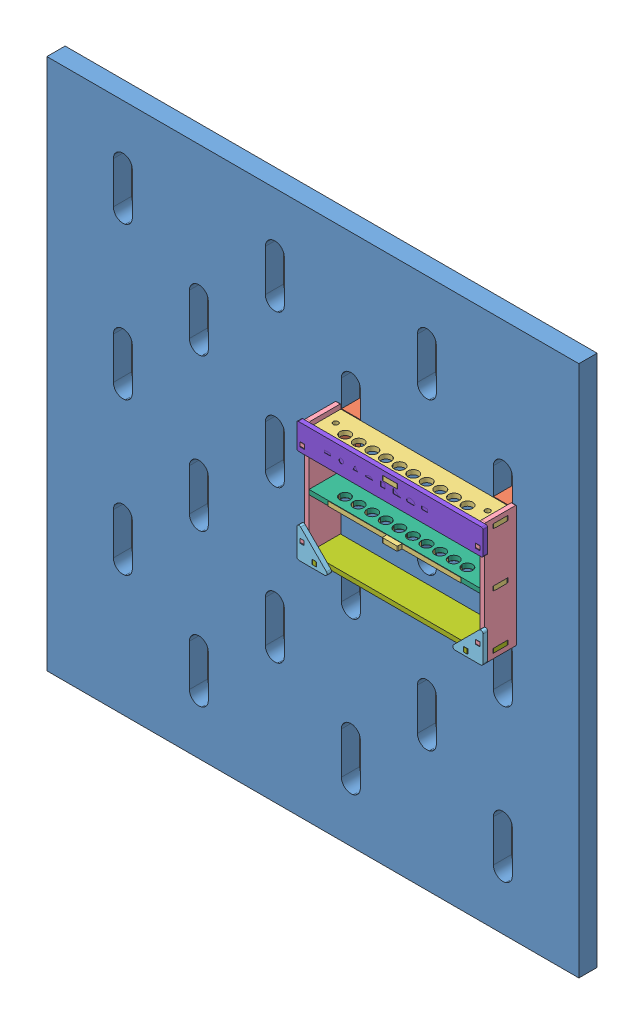
SolidWorks assembly 0 Органайзер надфили, configuration По умолчанию. Lengths in mm.
Overall size (350 350 45.89).
12 component instances, 8 part files, 40 mates.
Components (placement in the parent):
- 1 Стенка-1: 1 Стенка [По умолчанию] at origin size (350 350 12)
- 2 Кронштейн надфили-1: 2 Кронштейн надфили [По умолчанию] at (93.8 186.25 12) size (12.4 30 36.1)
- 2 Кронштейн надфили-2: 2 Кронштейн надфили [По умолчанию] at (193.8 186.25 12) size (12.4 30 36.1)
- 3 Полка верхняя надфили-1: 3 Полка верхняя надфили [По умолчанию] at (150.05 193.25 12.45) size (121.08 3 45.89)
- 4 Стенка надфиди-1: 4 Стенка надфиди [По умолчанию] at (206.3 159.35 22.9) size (3 80 24)
- 4 Стенка надфиди-2: 4 Стенка надфиди [По умолчанию] at (90.8 159.35 22.9) size (3 80 24)
- 7 уголок-1: 7 уголок [По умолчанию] at (211.2 120.25 33.2) size (22.07 22.07 3)
- 7 уголок-2: 7 уголок [По умолчанию] at (88.8 120.25 33.4) x (0 -1 0) z (0 0 1) size (22.07 22.07 3)
- 5 Полка средняя надфили-1: 5 Полка средняя надфили [По умолчанию] at (150.05 157.95 12.6) size (118.5 3 42.64)
- 6 Полка нижняя надфили-1: 6 Полка нижняя надфили [По умолчанию] at (150.05 122.25 12.7) size (118.5 3 45.64)
- 8 Маркировка-1: 8 Маркировка [По умолчанию] at (150.05 190.75 33.4) size (122.5 17 3)
- 3 Полка верхняя надфили-2: 3 Полка верхняя надфили [По умолчанию] at (150.05 157.75 12.45) size (121.08 3 45.89)
Mates (geometry in assembly coordinates):
- Концентричный1: concentric aligned: cylinder of 2 Кронштейн надфили-2 through (200.05 193.25 22.05) axis (0 1 0) radius 1.7; cylinder of 3 Полка верхняя надфили-1 through (200.05 196.25 22.05) axis (0 1 0) radius 1.7
- Концентричный2: concentric aligned: cylinder of 2 Кронштейн надфили-1 through (100.05 193.25 22.05) axis (0 1 0) radius 1.7; cylinder of 3 Полка верхняя надфили-1 through (100.05 196.25 22.05) axis (0 1 0) radius 1.7
- Параллельность1: parallel aligned: plane of 2 Кронштейн надфили-1 through (106.2 186.25 12) normal (0 0 -1); plane of 2 Кронштейн надфили-2 through (206.2 186.25 12) normal (0 0 -1)
- Параллельность2: parallel anti-aligned: plane of 2 Кронштейн надфили-1 through (106.2 186.25 12) normal (0 0 1); plane of 3 Полка верхняя надфили-1 through (150.05 196.25 12.45) normal (0 0 -1)
- Параллельность3: parallel anti-aligned: plane of 2 Кронштейн надфили-2 through (206.2 186.25 12) normal (0 0 1); plane of 3 Полка верхняя надфили-1 through (150.05 196.25 12.45) normal (0 0 -1)
- Совпадение5: coincident anti-aligned: plane of 2 Кронштейн надфили-2 through (206.2 193.25 12) normal (0 1 0); plane of 3 Полка верхняя надфили-1 through (150.05 193.25 12.45) normal (0 -1 0)
- Совпадение6: coincident anti-aligned: plane of 2 Кронштейн надфили-1 through (106.2 193.25 12) normal (0 1 0); plane of 3 Полка верхняя надфили-1 through (150.05 193.25 12.45) normal (0 -1 0)
- Совпадение7: coincident anti-aligned: plane of 3 Полка верхняя надфили-1 through (150.05 196.25 12.45) normal (0 1 0); plane of 4 Стенка надфиди-2 through (93.8 196.25 22.9) normal (0 -1 0)
- Совпадение8: coincident anti-aligned: plane of 3 Полка верхняя надфили-1 through (150.05 196.25 12.45) normal (0 1 0); plane of 4 Стенка надфиди-1 through (209.3 196.25 22.9) normal (0 -1 0)
- Совпадение9: coincident anti-aligned: plane of 3 Полка верхняя надфили-1 through (150.05 196.25 17.95) normal (0 0 -1); plane of 4 Стенка надфиди-1 through (209.3 159.35 17.95) normal (0 0 1)
- Совпадение10: coincident anti-aligned: plane of 3 Полка верхняя надфили-1 through (150.05 196.25 17.95) normal (0 0 -1); plane of 4 Стенка надфиди-2 through (93.8 159.35 17.95) normal (0 0 1)
- Совпадение11: coincident aligned: plane of 3 Полка верхняя надфили-1 through (90.8 196.25 12.45) normal (-1 0 0); plane of 4 Стенка надфиди-2 through (90.8 159.35 22.9) normal (-1 0 0)
- Совпадение12: coincident anti-aligned: plane of 3 Полка верхняя надфили-1 through (206.3 196.25 12.45) normal (1 0 0); plane of 4 Стенка надфиди-1 through (206.3 159.35 22.9) normal (-1 0 0)
- Совпадение13: coincident anti-aligned: plane of 4 Стенка надфиди-1 through (209.3 125.25 22.9) normal (0 -1 0); plane of 6 Полка нижняя надфили-1 through (150.05 125.25 12.7) normal (0 1 0)
- Совпадение14: coincident anti-aligned: plane of 4 Стенка надфиди-1 through (209.3 159.35 17.95) normal (0 0 1); plane of 6 Полка нижняя надфили-1 through (150.05 125.25 17.95) normal (0 0 -1)
- Совпадение15: coincident aligned: plane of 4 Стенка надфиди-1 through (209.3 159.35 22.9) normal (1 0 0); plane of 6 Полка нижняя надфили-1 through (209.3 125.25 12.7) normal (1 0 0)
- Совпадение16: coincident anti-aligned: plane of 4 Стенка надфиди-1 through (206.3 159.35 22.9) normal (-1 0 0); plane of 7 уголок-1 through (206.3 120.25 36.2) normal (1 0 0)
- Совпадение17: coincident aligned: plane of 4 Стенка надфиди-1 through (209.3 159.35 36.2) normal (0 0 1); plane of 7 уголок-1 through (211.2 120.25 36.2) normal (0 0 1)
- Совпадение18: coincident anti-aligned: plane of 7 уголок-1 through (211.2 122.25 36.2) normal (0 1 0); plane of 6 Полка нижняя надфили-1 through (150.05 122.25 12.7) normal (0 -1 0)
- Совпадение20: coincident anti-aligned: plane of 4 Стенка надфиди-1 through (209.3 159.35 27.85) normal (0 0 -1); plane of 5 Полка средняя надфили-1 through (150.05 160.95 27.85) normal (0 0 1)
- Совпадение21: coincident anti-aligned: plane of 4 Стенка надфиди-1 through (209.3 157.95 22.9) normal (0 1 0); plane of 5 Полка средняя надфили-1 through (150.05 157.95 12.6) normal (0 -1 0)
- Совпадение22: coincident aligned: plane of 4 Стенка надфиди-1 through (209.3 159.35 22.9) normal (1 0 0); plane of 5 Полка средняя надфили-1 through (209.3 160.95 12.6) normal (1 0 0)
- Совпадение23: coincident anti-aligned: plane of 7 уголок-2 through (88.8 122.25 36.4) normal (0 1 0); plane of 6 Полка нижняя надфили-1 through (150.05 122.25 12.7) normal (0 -1 0)
- Совпадение24: coincident anti-aligned: plane of 4 Стенка надфиди-2 through (90.8 159.35 22.9) normal (-1 0 0); plane of 7 уголок-2 through (90.8 120.25 36.4) normal (1 0 0)
- Совпадение25: coincident anti-aligned: plane of 4 Стенка надфиди-2 through (93.8 159.35 33.4) normal (0 0 1); plane of 7 уголок-2 through (88.8 120.25 33.4) normal (0 0 -1)
- Совпадение26: coincident anti-aligned: plane of 1 Стенка-1 through (0 0 12) normal (0 0 1); plane of 2 Кронштейн надфили-2 through (206.2 186.25 12) normal (0 0 -1)
- Параллельность4: parallel aligned: plane of 1 Стенка-1 through (0 300 12) normal (0 1 0); plane of 3 Полка верхняя надфили-1 through (150.05 196.25 12.45) normal (0 1 0)
- Концентричный3: concentric anti-aligned: cylinder of 1 Стенка-1 through (200 186.25 12) axis (0 0 -1) radius 6.25; cylinder of 2 Кронштейн надфили-2 through (200 186.25 -23.513) axis (0 0 1) radius 6.2
- Совпадение27: coincident anti-aligned: plane of 3 Полка верхняя надфили-1 through (150.05 193.25 12.45) normal (0 -1 0); plane of 8 Маркировка-1 through (145.05 193.25 36.4) normal (0 1 0)
- Совпадение28: coincident anti-aligned: plane of 4 Стенка надфиди-1 through (206.3 159.35 22.9) normal (-1 0 0); plane of 8 Маркировка-1 through (206.3 188.25 36.4) normal (1 0 0)
- Совпадение29: coincident anti-aligned: plane of 4 Стенка надфиди-2 through (93.8 159.35 33.4) normal (0 0 1); plane of 8 Маркировка-1 through (150.05 190.75 33.4) normal (0 0 -1)
- Концентричный4: concentric aligned: cylinder of 2 Кронштейн надфили-2 through (200.05 193.25 22.05) axis (0 1 0) radius 1.7; cylinder of 3 Полка верхняя надфили-2 through (200.05 160.75 22.05) axis (0 1 0) radius 1.7
- Концентричный5: concentric aligned: cylinder of 2 Кронштейн надфили-1 through (100.05 193.25 22.05) axis (0 1 0) radius 1.7; cylinder of 3 Полка верхняя надфили-2 through (100.05 160.75 22.05) axis (0 1 0) radius 1.7
- Параллельность5: parallel anti-aligned: plane of 2 Кронштейн надфили-1 through (106.2 186.25 12) normal (0 0 1); plane of 3 Полка верхняя надфили-2 through (150.05 160.75 12.45) normal (0 0 -1)
- Параллельность6: parallel anti-aligned: plane of 2 Кронштейн надфили-2 through (206.2 186.25 12) normal (0 0 1); plane of 3 Полка верхняя надфили-2 through (150.05 160.75 12.45) normal (0 0 -1)
- Совпадение30: coincident anti-aligned: plane of 4 Стенка надфиди-1 through (209.3 159.35 17.95) normal (0 0 1); plane of 3 Полка верхняя надфили-2 through (150.05 160.75 17.95) normal (0 0 -1)
- Совпадение31: coincident anti-aligned: plane of 4 Стенка надфиди-2 through (93.8 159.35 17.95) normal (0 0 1); plane of 3 Полка верхняя надфили-2 through (150.05 160.75 17.95) normal (0 0 -1)
- Совпадение32: coincident aligned: plane of 4 Стенка надфиди-2 through (90.8 159.35 22.9) normal (-1 0 0); plane of 3 Полка верхняя надфили-2 through (90.8 160.75 12.45) normal (-1 0 0)
- Совпадение33: coincident anti-aligned: plane of 4 Стенка надфиди-1 through (206.3 159.35 22.9) normal (-1 0 0); plane of 3 Полка верхняя надфили-2 through (206.3 160.75 12.45) normal (1 0 0)
- Совпадение34: coincident anti-aligned: plane of 4 Стенка надфиди-1 through (209.3 160.75 22.9) normal (0 -1 0); plane of 3 Полка верхняя надфили-2 through (150.05 160.75 12.45) normal (0 1 0)
